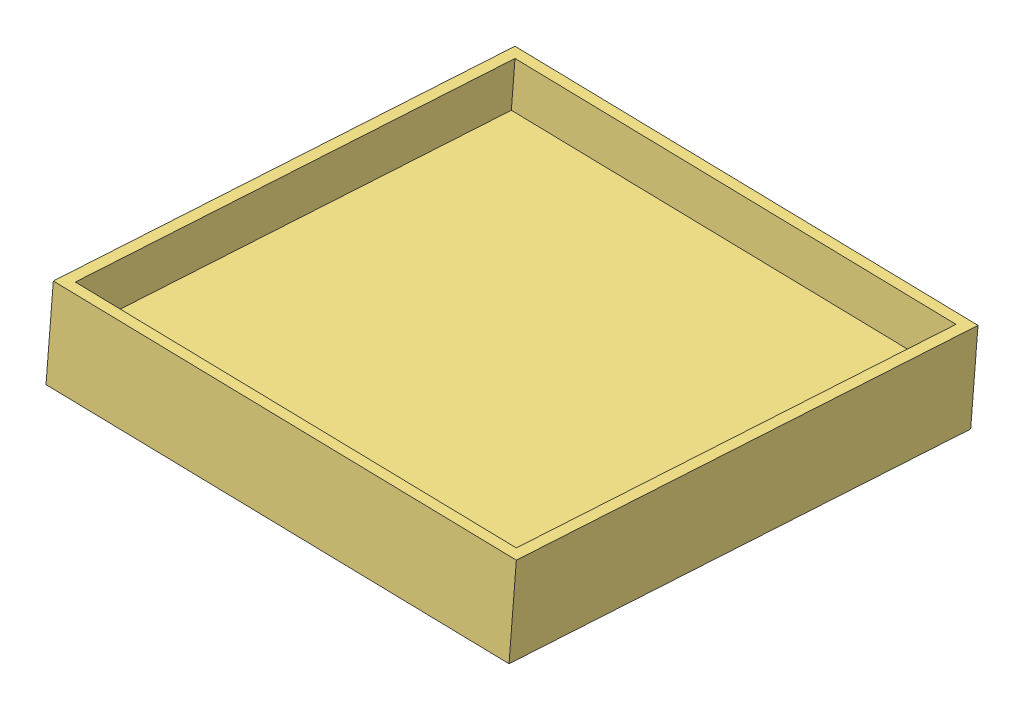
SolidWorks assembly Platform, configuration Default. Lengths in mm.
Overall size (1056.13 513.05 1061.74).
3 component instances, 3 part files, 7 mates.
Components (placement in the parent):
- Base-1: Base [Default] at (-21.7654 125 -1.8898) size (100 125 100)
- Joint-1: Joint [Default] at (-21.378 259.9957 -1.8898) x (0 0 -1) z (0.999755 -0.022141 0) size (100 150 100)
- Plane-1: Plane [Default] at (-18.3897 394.9302 -2.9539) x (0.001346 0.060789 0.99815) z (-0.999755 0.022141 0) size (1050 225 1050)
Mates (geometry in assembly coordinates):
- Parallel2: parallel: plane of assembly through (0 0 0) normal (0 0 1); plane of Base-1 through (-21.7654 125 -1.8898) normal (0 0 1); plane of assembly
- Parallel3: parallel: plane of assembly through (0 0 0) normal (0 1 0); plane of Base-1 through (-21.7654 125 -1.8898) normal (0 1 0); plane of assembly
- Parallel4: parallel: plane of assembly through (0 0 0) normal (1 0 0); plane of Base-1 through (-21.7654 125 -1.8898) normal (1 0 0); plane of assembly
- Concentric1: concentric anti-aligned: cylinder of Base-1 through (-21.7654 242.5 5.6102) axis (0 0 1) radius 5; cylinder of Joint-1 through (-21.7654 242.5 30.6102) axis (0 0 -1) radius 5
- Coincident2: coincident aligned: plane of Base-1 through (-34.2654 250 30.6102) normal (0 0 1); plane of Joint-1 through (-21.7654 242.5 30.6102) normal (0 0 1)
- Concentric2: concentric anti-aligned: cylinder of Joint-1 through (-11.2783 377.3008 -1.8898) axis (0.999755 -0.022141 0) radius 5; cylinder of Plane-1 through (13.7156 376.7473 -1.8898) axis (-0.999755 0.022141 0) radius 5
- Coincident3: coincident aligned: plane of Joint-1 through (13.8817 384.2455 10.6102) normal (0.999755 -0.022141 0); plane of Plane-1 through (13.7156 376.7473 -1.8898) normal (0.999755 -0.022141 0)
